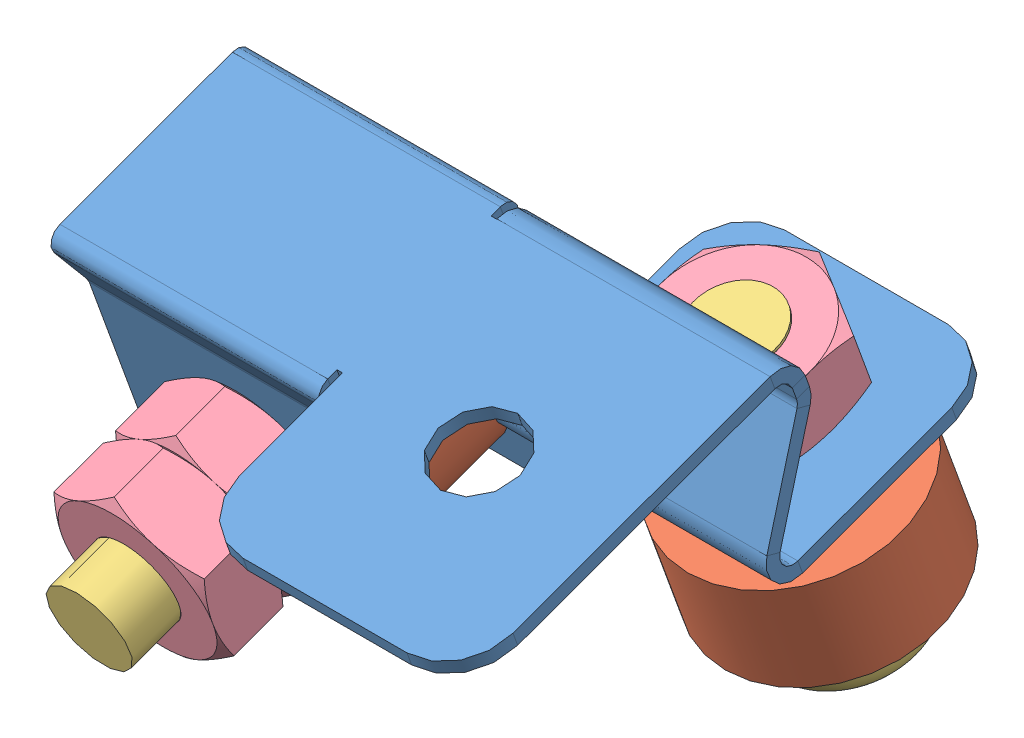
SolidWorks assembly table_support_right_assembly, configuration По умолчанию. Lengths in mm.
Overall size (20 15.82 22.62).
9 component instances, 4 part files, 16 mates.
Components (placement in the parent):
- table_support_2-1: table_support_2 [По умолчанию] at (17.3508 5.4643 12.1497) size (20 13.19 19.98)
- short_roller-1: short_roller [По умолчанию] at (12.2508 1.2828 8.9867) x (0 0.939693 0.34202) z (1 0 0) size (8 4 8)
- short_roller-2: short_roller [По умолчанию] at (22.3508 -4.266 3.2234) x (1 0 0) z (0 -0.34202 0.939693) size (8 4 8)
- pan slot head_am-2: pan slot head_am [B18.6.7M - M3 x 0.5 x 10 Slotted PHMS --10N] at (22.3508 -6.5212 2.4026) x (0 0.939693 0.34202) z (-0.34202 -0.321394 0.883022) size (12.48 5.6 5.6)
- pan slot head_am-3: pan slot head_am [B18.6.7M - M3 x 0.5 x 13 Slotted PHMS --13N] at (12.2508 2.487 5.6782) x (0 -0.34202 0.939693) z (-0.939693 0.321394 0.116978) size (15.48 5.6 5.6)
- hex nut style 1_am-1: hex nut style 1_am [B18.2.4.1M - Hex nut, Style 1,  M3 x 0.5 --D-N] at (22.3508 5.037 6.6094) x (1 0 0) z (0 0.939693 0.34202) size (5.5 6.35 2.4)
- hex nut style 1_am-2: hex nut style 1_am [B18.2.4.1M - Hex nut, Style 1,  M3 x 0.5 --D-N] at (22.3508 0.0566 4.7967) x (1 0 0) z (0 -0.939693 -0.34202) size (5.5 6.35 2.4)
- hex nut style 1_am-3: hex nut style 1_am [B18.2.4.1M - Hex nut, Style 1,  M3 x 0.5 --D-N] at (12.2508 -1.3166 16.1283) x (1 0 0) z (0 -0.34202 0.939693) size (5.5 6.35 2.4)
- hex nut style 1_am-4: hex nut style 1_am [B18.2.4.1M - Hex nut, Style 1,  M3 x 0.5 --D-N] at (12.2508 -2.1374 18.3836) x (1 0 0) z (0 -0.34202 0.939693) size (5.5 6.35 2.4)
Mates (geometry in assembly coordinates):
- Концентричный1: concentric aligned: cylinder of table_support_2-1 through (12.2508 -3.5375 22.2303) axis (0 0.34202 -0.939693) radius 1.5; cylinder of short_roller-1 through (12.2508 -0.0853 12.7454) axis (0 0.34202 -0.939693) radius 1.75
- Расстояние1: distance = 0.7 mm anti-aligned: plane of short_roller-1 through (12.2508 -0.0853 12.7454) normal (0 -0.34202 0.939693); plane of table_support_2-1 through (17.3508 9.0722 16.8234) normal (0 0.34202 -0.939693)
- Концентричный2: concentric anti-aligned: cylinder of table_support_2-1 through (22.3508 -1.7713 4.1314) axis (0 0.939693 0.34202) radius 1.5; cylinder of short_roller-2 through (22.3508 -0.5072 4.5915) axis (0 -0.939693 -0.34202) radius 1.75
- Расстояние2: distance = 3 mm anti-aligned: plane of short_roller-2 through (22.3508 -0.5072 4.5915) normal (0 0.939693 0.34202); plane of table_support_2-1 through (17.3508 -2.7398 19.4968) normal (0 -0.939693 -0.34202)
- Концентричный3: concentric aligned: cylinder of short_roller-2 through (22.3508 -0.5072 4.5915) axis (0 -0.939693 -0.34202) radius 1.75; cylinder of pan slot head_am-2 through (22.3508 -30.3894 -6.2847) axis (0 -0.939693 -0.34202) radius 2.8
- Совпадение1: coincident anti-aligned: plane of short_roller-2 through (22.3508 -4.266 3.2234) normal (0 -0.939693 -0.34202); plane of pan slot head_am-2 through (20.9412 -4.0905 2.7413) normal (0 0.939693 0.34202)
- Концентричный4: concentric aligned: cylinder of table_support_2-1 through (12.2508 -3.5375 22.2303) axis (0 0.34202 -0.939693) radius 1.5; cylinder of pan slot head_am-3 through (12.2508 11.1743 -18.19) axis (0 0.34202 -0.939693) radius 2.8
- Совпадение2: coincident anti-aligned: plane of table_support_2-1 through (17.3508 11.0631 11.3536) normal (0 0.34202 -0.939693); plane of pan slot head_am-3 through (12.7638 2.9907 8.4155) normal (0 -0.34202 0.939693)
- Концентричный5: concentric aligned: cylinder of table_support_2-1 through (22.3508 -1.7713 4.1314) axis (0 0.939693 0.34202) radius 1.5; cylinder of hex nut style 1_am-1 through (22.3508 -18.4906 -1.9539) axis (0 0.939693 0.34202) radius 1.5
- Совпадение3: coincident anti-aligned: plane of table_support_2-1 through (17.3508 -2.2699 19.6678) normal (0 0.939693 0.34202); plane of hex nut style 1_am-1 through (22.3508 3.8678 2.8047) normal (0 -0.939693 -0.34202)
- Концентричный6: concentric anti-aligned: cylinder of table_support_2-1 through (22.3508 -1.7713 4.1314) axis (0 0.939693 0.34202) radius 1.5; cylinder of hex nut style 1_am-2 through (22.3508 23.5842 13.3601) axis (0 -0.939693 -0.34202) radius 1.5
- Совпадение4: coincident anti-aligned: plane of table_support_2-1 through (17.3508 -2.7398 19.4968) normal (0 -0.939693 -0.34202); plane of hex nut style 1_am-2 through (22.3508 1.2258 8.6015) normal (0 0.939693 0.34202)
- Концентричный7: concentric anti-aligned: cylinder of table_support_2-1 through (12.2508 -3.5375 22.2303) axis (0 0.34202 -0.939693) radius 1.5; cylinder of hex nut style 1_am-3 through (12.2508 7.2468 -7.3992) axis (0 -0.34202 0.939693) radius 1.5
- Совпадение5: coincident anti-aligned: plane of table_support_2-1 through (17.3508 8.9012 17.2933) normal (0 -0.34202 0.939693); plane of hex nut style 1_am-3 through (12.2508 2.4882 14.9591) normal (0 0.34202 -0.939693)
- Концентричный8: concentric aligned: cone of hex nut style 1_am-3 through (12.2508 -1.3166 16.1283) axis (0 -0.34202 0.939693); cylinder of hex nut style 1_am-4 through (12.2508 6.4259 -5.144) axis (0 -0.34202 0.939693) radius 1.5
- Совпадение6: coincident anti-aligned: plane of hex nut style 1_am-3 through (12.2508 1.6674 17.2144) normal (0 -0.34202 0.939693); plane of hex nut style 1_am-4 through (12.2508 1.6674 17.2144) normal (0 0.34202 -0.939693)
